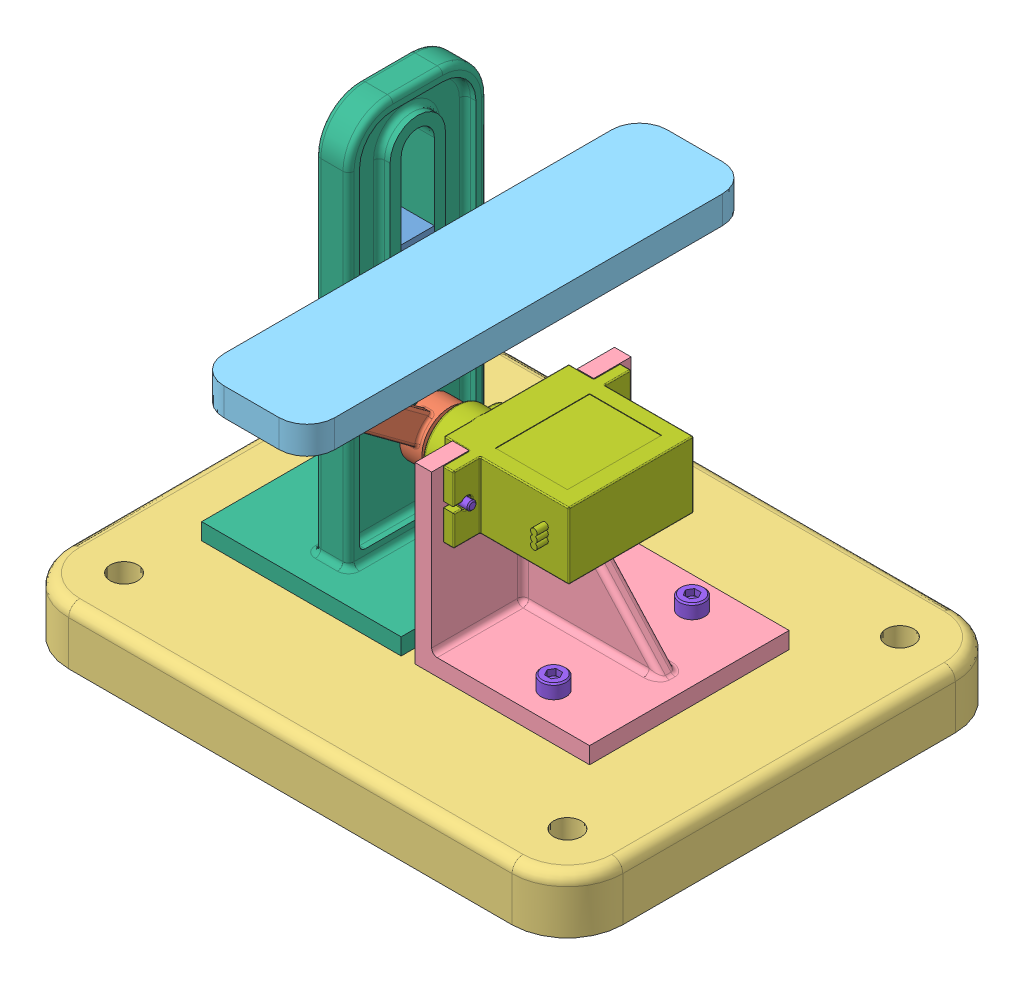
SolidWorks assembly motstu, configuration Default. Lengths in mm.
Overall size (100 83 80).
14 component instances, 8 part files, 30 mates.
Components (placement in the parent):
- clip-1: clip [Default] at (-19.4643 85.1655 1.78) x (0 0 1) z (0 1 0) size (10 8 7)
- servo arm-1: servo arm [Default] at (-2.4643 73.8343 19.0939) x (0 -0.804263 0.594273) z (-1 0 0) size (10 38 4)
- base-1: base [Default] at (5.5357 29.4202 1.78) size (100 10 80)
- servo holder-1: servo holder [Default] at (7.5357 40.9202 1.78) x (-1 0 0) z (0 0 -1) size (31.5 31.5 36)
- shelf-1: shelf [Default] at (-1.4643 87.6655 1.78) x (0 0 -1) z (-1 0 0) size (80 5 26)
- slot-1: slot [Default] at (-14.4643 39.4202 1.78) size (36 73 36)
- Micro Servo SG92R 180-1: Micro Servo SG92R 180 [Valor predeterminado] at (11.0357 64.9202 1.78) x (0 0 -1) z (0 1 0) size (32 29 12)
- socket head cap screw_am-1: socket head cap screw_am [B18.3.1M - 2.5 x 0.45 x 8 Hex SHCS -- 8NHX] at (25.5357 44.9202 -10.72) x (0 -1 0) z (0 0 1) size (10.5 4.5 4.5)
- socket head cap screw_am-2: socket head cap screw_am [B18.3.1M - 2.5 x 0.45 x 8 Hex SHCS -- 8NHX] at (25.5357 44.9202 14.28) x (0 -1 0) z (0 0 1) size (10.5 4.5 4.5)
- socket head cap screw_am-3: socket head cap screw_am [B18.3.1M - 2.5 x 0.45 x 8 Hex SHCS -- 8NHX] at (-4.4643 44.9202 1.78) x (0 -1 0) z (0 0 1) size (10.5 4.5 4.5)
- socket head cap screw_am-4: socket head cap screw_am [B18.3.1M - 2.5 x 0.45 x 8 Hex SHCS -- 8NHX] at (-24.4643 44.9202 1.78) x (0 -1 0) z (0 0 1) size (10.5 4.5 4.5)
- socket head cap screw_am-5: socket head cap screw_am [B18.3.1M - 2.5 x 0.45 x 8 Hex SHCS -- 8NHX] at (-21.9643 85.1655 1.78) size (10.5 4.5 4.5)
- socket head cap screw_am-6: socket head cap screw_am [B18.3.1M - 1.6 x 0.35 x 6 Hex SHCS -- 6NHX] at (4.4357 64.9202 15.405) size (7.6 3 3)
- socket head cap screw_am-7: socket head cap screw_am [B18.3.1M - 1.6 x 0.35 x 6 Hex SHCS -- 6NHX] at (4.4357 64.9202 -11.845) size (7.6 3 3)
Mates (geometry in assembly coordinates):
- Concentric1: concentric aligned: cylinder of base-1 through (25.5357 29.4202 -10.72) axis (0 1 0) radius 1.5; cylinder of servo holder-1 through (25.5357 32.4202 -10.72) axis (0 1 0) radius 1.5
- Concentric2: concentric aligned: cylinder of base-1 through (25.5357 29.4202 14.28) axis (0 1 0) radius 1.5; cylinder of servo holder-1 through (25.5357 32.4202 14.28) axis (0 1 0) radius 1.5
- Concentric3: concentric aligned: cylinder of base-1 through (-24.4643 29.4202 1.78) axis (0 1 0) radius 1.5; cylinder of slot-1 through (-24.4643 39.4202 1.78) axis (0 1 0) radius 1.5
- Concentric4: concentric aligned: cylinder of base-1 through (-4.4643 29.4202 1.78) axis (0 1 0) radius 1.5; cylinder of slot-1 through (-4.4643 39.4202 1.78) axis (0 1 0) radius 1.5
- Coincident1: coincident anti-aligned: plane of base-1 through (5.5357 39.4202 1.78) normal (0 1 0); plane of slot-1 through (-14.4643 39.4202 1.78) normal (0 -1 0)
- Coincident2: coincident anti-aligned: plane of base-1 through (5.5357 39.4202 1.78) normal (0 1 0); plane of servo holder-1 through (37.5357 39.4202 -16.22) normal (0 -1 0)
- Slot1: slot anti-aligned: plane of slot-1 through (-81.4643 102.4202 4.78) normal (0 0 -1); cylinder of shelf-1 through (-13.4643 85.1655 1.78) axis (-1 0 0) radius 1.425; cylinder of slot-1 through (-81.4643 102.4202 1.78) axis (1 0 0) radius 3
- Coincident3: coincident anti-aligned: plane of clip-1 through (-11.4643 81.6655 4.78) normal (0 0 1); plane of slot-1 through (-81.4643 102.4202 4.78) normal (0 0 -1)
- Coincident4: coincident anti-aligned: plane of clip-1 through (-17.4643 85.1655 1.78) normal (1 0 0); plane of slot-1 through (-17.4643 112.4202 -10.72) normal (-1 0 0)
- Coincident5: coincident anti-aligned: plane of clip-1 through (-17.4643 85.1655 1.78) normal (1 0 0); plane of shelf-1 through (-17.4643 87.6655 1.78) normal (-1 0 0)
- Coincident6: coincident anti-aligned: plane of clip-1 through (-11.4643 87.6655 -1.22) normal (0 -1 0); plane of shelf-1 through (-1.4643 87.6655 1.78) normal (0 1 0)
- Coincident7: coincident anti-aligned: plane of servo holder-1 through (16.0357 70.9202 -9.47) normal (0 0 1); plane of Micro Servo SG92R 180-1 through (27.0357 58.9202 -9.47) normal (0 0 -1)
- Coincident8: coincident anti-aligned: plane of servo holder-1 through (16.0357 58.9202 13.03) normal (0 1 0); plane of Micro Servo SG92R 180-1 through (27.0357 58.9202 13.03) normal (0 -1 0)
- Concentric5: concentric anti-aligned: cylinder of servo arm-1 through (-0.4643 64.9202 7.03) axis (-1 0 0) radius 2.25; cylinder of Micro Servo SG92R 180-1 through (-1.9643 64.9202 7.03) axis (1 0 0) radius 2.25
- Coincident10: coincident anti-aligned: plane of servo holder-1 through (9.0357 40.9202 -16.22) normal (1 0 0); plane of Micro Servo SG92R 180-1 through (9.0357 64.9202 -11.845) normal (-1 0 0)
- Concentric6: concentric aligned: cylinder of servo holder-1 through (25.5357 32.4202 -10.72) axis (0 1 0) radius 1.5; cylinder of socket head cap screw_am-1 through (25.5357 76.6702 -10.72) axis (0 1 0) radius 2.25
- Coincident11: coincident anti-aligned: plane of servo holder-1 through (37.5357 42.4202 -16.22) normal (0 1 0); plane of socket head cap screw_am-1 through (27.7857 42.4202 -10.72) normal (0 -1 0)
- Concentric7: concentric aligned: cylinder of servo holder-1 through (25.5357 32.4202 14.28) axis (0 1 0) radius 1.5; cylinder of socket head cap screw_am-2 through (25.5357 76.6702 14.28) axis (0 1 0) radius 2.25
- Coincident12: coincident anti-aligned: plane of servo holder-1 through (37.5357 42.4202 -16.22) normal (0 1 0); plane of socket head cap screw_am-2 through (27.7857 42.4202 14.28) normal (0 -1 0)
- Concentric8: concentric aligned: cylinder of slot-1 through (-4.4643 39.4202 1.78) axis (0 1 0) radius 1.5; cylinder of socket head cap screw_am-3 through (-4.4643 76.6702 1.78) axis (0 1 0) radius 2.25
- Coincident13: coincident anti-aligned: plane of slot-1 through (-14.4643 42.4202 1.78) normal (0 1 0); plane of socket head cap screw_am-3 through (-2.2143 42.4202 1.78) normal (0 -1 0)
- Concentric9: concentric aligned: cylinder of slot-1 through (-24.4643 39.4202 1.78) axis (0 1 0) radius 1.5; cylinder of socket head cap screw_am-4 through (-24.4643 76.6702 1.78) axis (0 1 0) radius 2.25
- Coincident14: coincident anti-aligned: plane of slot-1 through (-14.4643 42.4202 1.78) normal (0 1 0); plane of socket head cap screw_am-4 through (-22.2143 42.4202 1.78) normal (0 -1 0)
- Concentric10: concentric anti-aligned: cylinder of clip-1 through (-19.4643 85.1655 1.78) axis (1 0 0) radius 1.425; cylinder of socket head cap screw_am-5 through (-53.7143 85.1655 1.78) axis (-1 0 0) radius 2.25
- Coincident15: coincident anti-aligned: plane of clip-1 through (-19.4643 85.1655 1.78) normal (-1 0 0); plane of socket head cap screw_am-5 through (-19.4643 87.4155 1.78) normal (1 0 0)
- Concentric11: concentric aligned: cylinder of servo holder-1 through (16.0357 64.9202 15.405) axis (-1 0 0) radius 1; cylinder of socket head cap screw_am-6 through (-27.3143 64.9202 15.405) axis (-1 0 0) radius 1.5
- Coincident16: coincident anti-aligned: plane of servo holder-1 through (6.0357 40.9202 -16.22) normal (-1 0 0); plane of socket head cap screw_am-6 through (6.0357 66.4202 15.405) normal (1 0 0)
- Concentric12: concentric aligned: cylinder of servo holder-1 through (16.0357 64.9202 -11.845) axis (-1 0 0) radius 1; cylinder of socket head cap screw_am-7 through (-27.3143 64.9202 -11.845) axis (-1 0 0) radius 1.5
- Coincident17: coincident anti-aligned: plane of servo holder-1 through (6.0357 40.9202 -16.22) normal (-1 0 0); plane of socket head cap screw_am-7 through (6.0357 66.4202 -11.845) normal (1 0 0)
- Distance1: distance = 1 mm anti-aligned: plane of Micro Servo SG92R 180-1 through (0.5357 64.9202 7.03) normal (-1 0 0); plane of servo arm-1 through (-0.4643 64.9202 7.03) normal (1 0 0)
